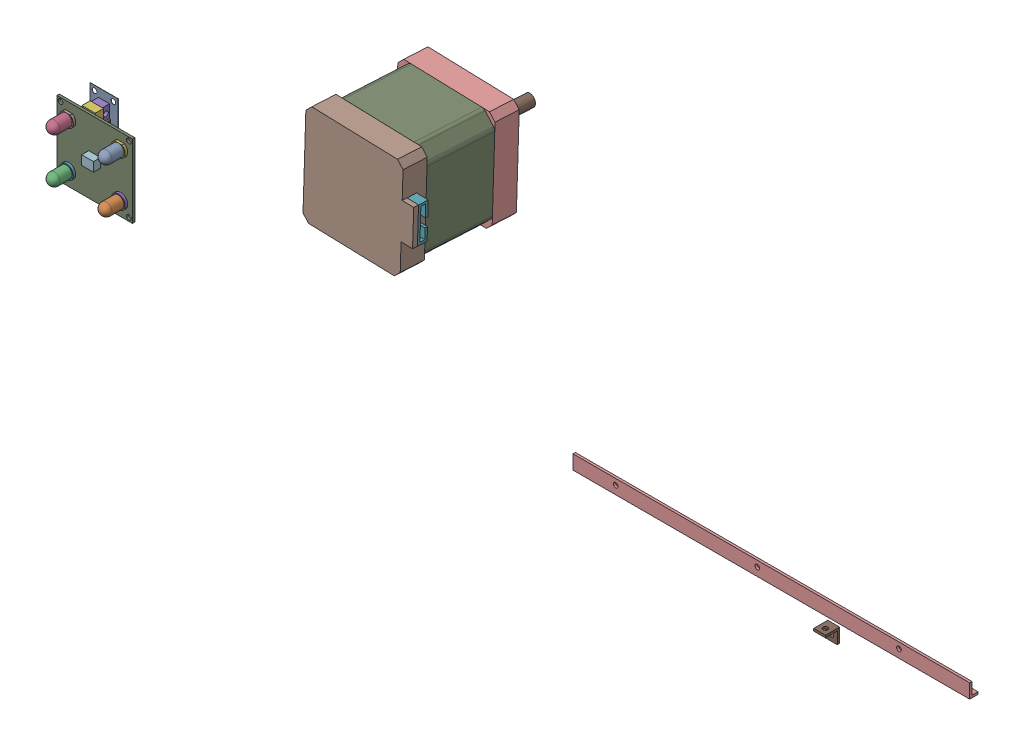
SolidWorks assembly Ensamblaje1, configuration Predeterminado. Lengths in mm.
Overall size (262.53 180.19 153.53).
6 component instances, 6 part files, 2 mates.
Components (placement in the parent):
- Final de carrera-1: Final de carrera [Predeterminado] at (-36.9029 2.3642 -23.5301) size (12 20 7.1)
- motor-1: motor [Predeterminado] at (27.732 -10.5828 -118.6016) x (0.999652 -0.003272 0.026191) z (-0.026088 0.028262 0.99926) size (47.3 42.3 50)
- rotor-motor-1: rotor-motor [Predeterminado] at (31.0304 -21.64 -117.202) x (-0.466025 -0.884678 0.012855) z (0.026088 -0.028262 -0.99926) size (5 5 26)
- TCS3200_Sensor-1: TCS3200_Sensor [Predeterminado] at (-6.1556 15.7277 -0.8071) size (32 31 9.6)
- ala1-1: ala1 [Predeterminado] at (114.3331 -123.5214 -134.7702) size (168.05 6 3.5)
- Ala2-1: Ala2 [Predeterminado] at (158.713 -140.6404 -144.7342) size (5 6 6)
Mates (geometry in assembly coordinates):
- Concentric1: concentric anti-aligned: cylinder of motor-1 through (27.4699 -7.6309 -117.6912) axis (0.026088 -0.028262 -0.99926) radius 2.5; cylinder of rotor-motor-1 through (28.1482 -8.3657 -143.6719) axis (-0.026088 0.028262 0.99926) radius 2.5
- Coincident1: coincident anti-aligned: plane of motor-1 through (27.4699 -7.6309 -117.6912) normal (0.026088 -0.028262 -0.99926); plane of rotor-motor-1 through (27.4699 -7.6309 -117.6912) normal (-0.026088 0.028262 0.99926)
